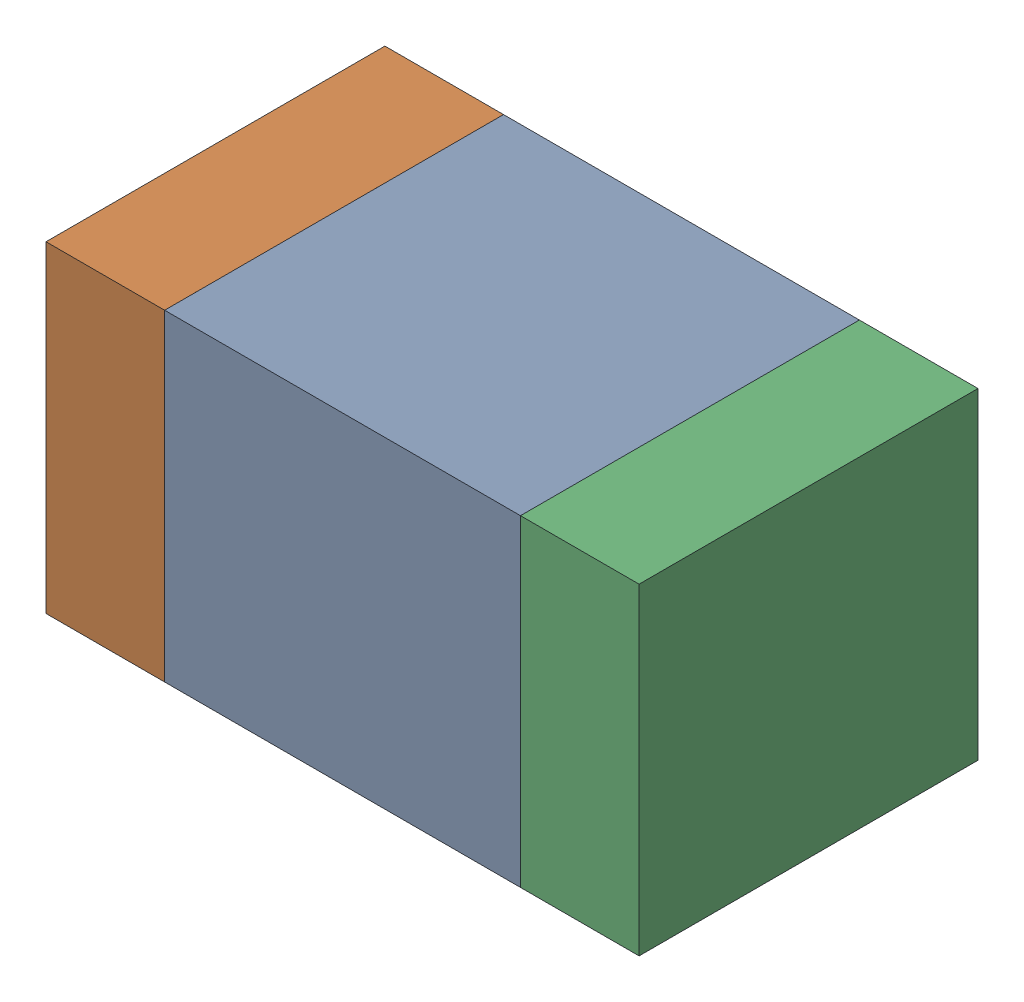
SolidWorks assembly C437PCB, configuration Default. Lengths in mm.
Overall size (1.75 0.95 1).
6 component instances, 2 part files, 0 mates.
Components (placement in the parent):
- 761616112-1: 761616112 [Default] at (78.2 85.1 0) size (1.05 0.95 1)
  - Extruded_14-1: Extruded_14 [Default] at origin size (1.05 0.95 1)
- 761616248-1: 761616248 [Default] at (77.5 85.1 0) size (0.35 0.95 1)
  - Extruded_15-1: Extruded_15 [Default] at origin size (0.35 0.95 1)
- 761616248-2: 761616248 [Default] at (78.9 85.1 0) size (0.35 0.95 1)
  - Extruded_15-1: Extruded_15 [Default] at origin size (0.35 0.95 1)
